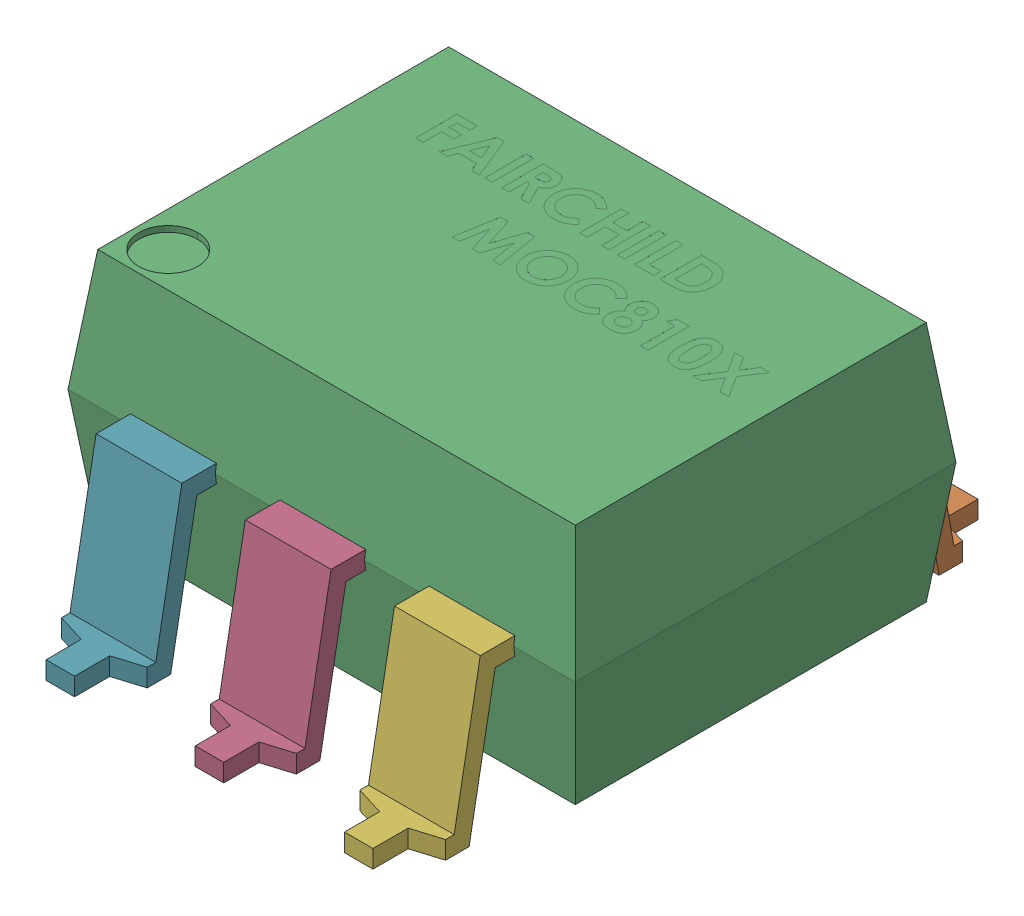
SolidWorks assembly SMD DIP-6_1.step, configuration Default. Lengths in mm.
Overall size (8.63 4.63 10.3).
7 component instances, 2 part files, 0 mates.
Components (placement in the parent):
- MOC810X_SOIC6_PIN_1.step-64: MOC810X_SOIC6_PIN_1.step [Default] at (2.5236 0.1223 -5.1276) x (-1 0 0) z (0 0 -1) size (1.46 2.72 2.11)
- MOC810X_SOIC6_PIN_1.step-65: MOC810X_SOIC6_PIN_1.step [Default] at (5.0636 0.1223 -5.1276) x (-1 0 0) z (0 0 -1) size (1.46 2.72 2.11)
- MOC810X_SOIC6_BODY_1.step-11: MOC810X_SOIC6_BODY_1.step [Default] at (-2.5239 -0.0302 1.3524) size (8.63 4.12 6.48)
- MOC810X_SOIC6_PIN_1.step-66: MOC810X_SOIC6_PIN_1.step [Default] at (1.0636 0.1223 1.3524) size (1.46 2.72 2.11)
- MOC810X_SOIC6_PIN_1.step-67: MOC810X_SOIC6_PIN_1.step [Default] at (-0.0164 0.1223 -5.1276) x (-1 0 0) z (0 0 -1) size (1.46 2.72 2.11)
- MOC810X_SOIC6_PIN_1.step-68: MOC810X_SOIC6_PIN_1.step [Default] at (3.6036 0.1223 1.3524) size (1.46 2.72 2.11)
- MOC810X_SOIC6_PIN_1.step-69: MOC810X_SOIC6_PIN_1.step [Default] at (-1.4764 0.1223 1.3524) size (1.46 2.72 2.11)
